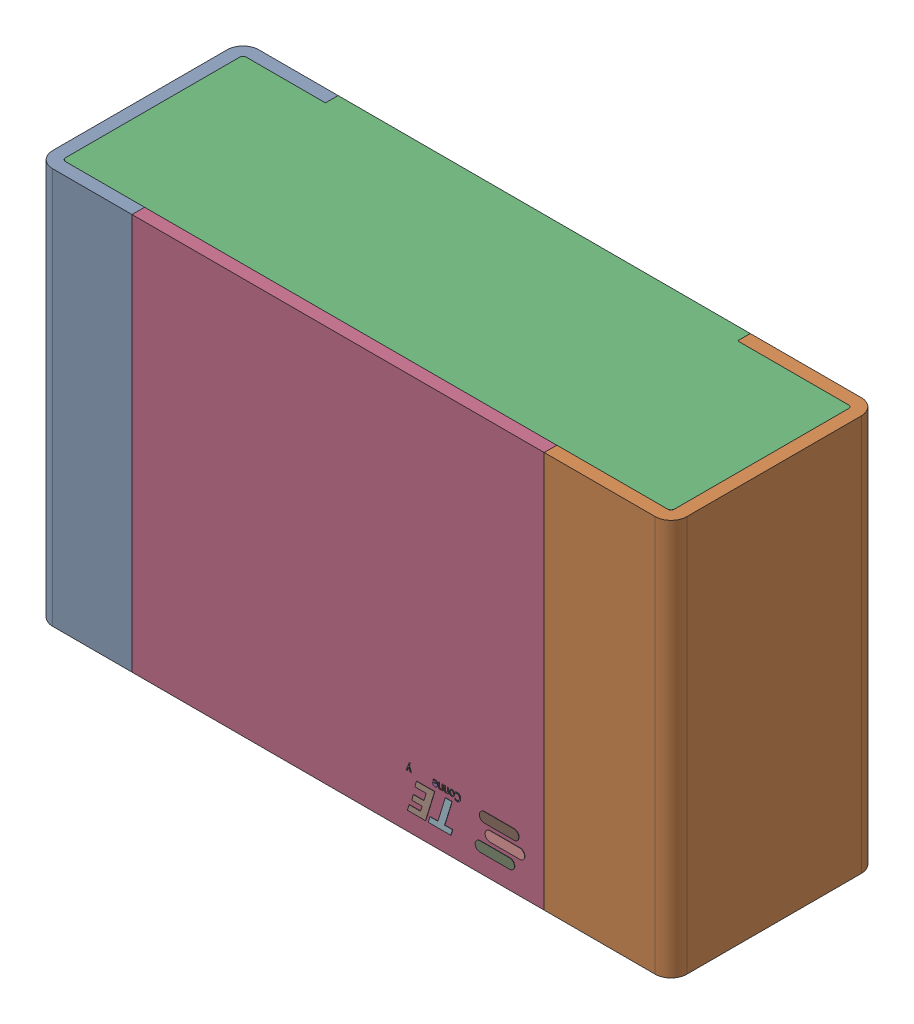
SolidWorks assembly RLH5.step, configuration Default. Lengths in mm.
Overall size (2 1.25 0.65).
5 component instances, 4 part files, 0 mates.
Components (placement in the parent):
- Res_TE_Connectivity_CPF0805B66R5E1_eec.step-1: Res_TE_Connectivity_CPF0805B66R5E1_eec.step [Default] at (5.191 3.368 0) x (-1 0 0) z (0 0 1) size (2 1.25 0.65)
  - 1.step-1: 1.step [Default] at origin size (2 1.25 0.65)
  - 2.step-1: 2.step [Default] at origin size (1.92 1.25 0.61)
  - 3.step-1: 3.step [Default] at origin size (1.3 1.25 0.04)
  - TE connectivity Logo 1 (2).step-1: TE connectivity Logo 1 (2).step [Default] at (5.4285 0.313 0.551) x (-1 0 0) z (0 0 1) size (0.37 0.13 0.11)
